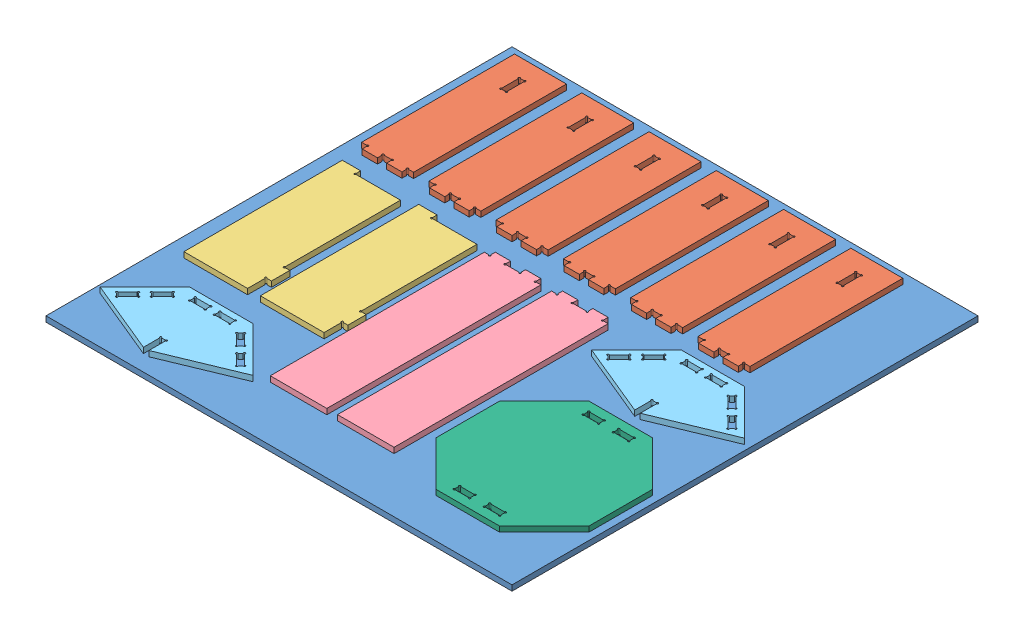
SolidWorks assembly layout, configuration Default. Lengths in mm.
Overall size (1524 36 1524).
14 component instances, 6 part files, 5 mates.
Components (placement in the parent):
- ply-1: ply [Default] at (-568.4277 938.2509 2026.6102) size (1524 18 1524)
- Part1-1: Part1 [Default] at (-525.9311 974.2509 536.9929) x (0 -1 0) z (-1 0 0) size (18 518 170)
- Part1-2: Part1 [Default] at (-305.9311 974.2509 536.9929) x (0 -1 0) z (-1 0 0) size (18 518 170)
- Part1-3: Part1 [Default] at (-85.9311 974.2509 536.9929) x (0 -1 0) z (-1 0 0) size (18 518 170)
- Part1-4: Part1 [Default] at (134.0689 974.2509 536.9929) x (0 -1 0) z (-1 0 0) size (18 518 170)
- Part1-5: Part1 [Default] at (354.0689 974.2509 536.9929) x (0 -1 0) z (-1 0 0) size (18 518 170)
- Part1-6: Part1 [Default] at (574.0689 974.2509 536.9929) x (0 -1 0) z (-1 0 0) size (18 518 170)
- Stiffener-1: Stiffener [Default] at (-2828.0492 1465.0757 881.246) x (1 0 0) z (0 1 0) size (226.27 518 18)
- Stiffener-2: Stiffener [Default] at (-2578.0492 1465.0757 881.246) x (1 0 0) z (0 1 0) size (226.27 518 18)
- Part2-1: Part2 [Default] at (152.581 694.6705 1151.7764) x (1 0 0) z (0 1 0) size (185 718 18)
- Part2-2: Part2 [Default] at (372.581 694.6705 1151.7764) x (1 0 0) z (0 1 0) size (185 718 18)
- Part5-1: Part5 [Default] at (2836.1292 974.2509 -9933.6704) x (0 0 -1) z (1 0 0) size (246.27 18 500)
- table_top-1: table_top [Default] at (682.1942 955.7624 1647.7497) size (500 18 500)
- Part5-2: Part5 [Default] at (1854.9962 974.2509 -9308.0438) x (0 0 -1) z (1 0 0) size (246.27 18 500)
Mates (geometry in assembly coordinates):
- Coincident1: coincident anti-aligned: plane of ply-1 through (-568.4277 956.2509 2026.6102) normal (0 1 0); plane of Part1-1 through (-525.9311 956.2509 536.9929) normal (0 -1 0)
- Coincident3: coincident anti-aligned: plane of ply-1 through (-568.4277 956.2509 2026.6102) normal (0 1 0); plane of Stiffener-1 through (-2828.0492 956.2509 881.246) normal (0 -1 0)
- Coincident4: coincident anti-aligned: plane of ply-1 through (-568.4277 956.2509 2026.6102) normal (0 1 0); plane of Part2-1 through (152.581 956.2509 1151.7764) normal (0 -1 0)
- Coincident5: coincident anti-aligned: plane of ply-1 through (-568.4277 956.2509 2026.6102) normal (0 1 0); plane of Part5-1 through (2836.1292 956.2509 -9933.6704) normal (0 -1 0)
- Coincident6: coincident anti-aligned: plane of ply-1 through (-568.4277 956.2509 2026.6102) normal (0 1 0); plane of Part5-2 through (1854.9962 956.2509 -9308.0438) normal (0 -1 0)
